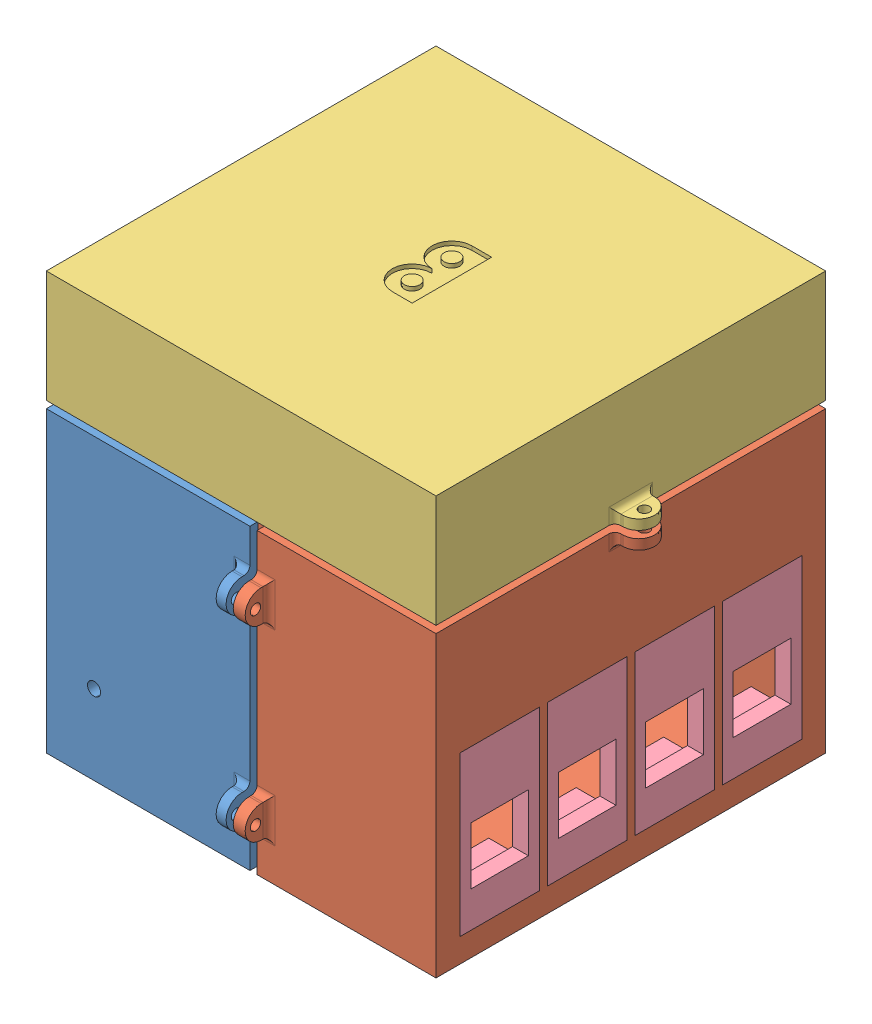
SolidWorks assembly box2, configuration Default. Lengths in mm.
Overall size (110 105 110).
7 component instances, 4 part files, 6 mates.
Components (placement in the parent):
- 2lx-2: 2lx [Default] at (21.703 36.8071 99.9525) size (57.2 80 110)
- 2rx-4: 2rx [Default] at (68.203 36.8071 99.9525) x (-1 0 0) z (0 0 -1) size (56 80 110)
- 2top-2: 2top [Default] at (44.203 141.8071 99.9525) x (-1 0 0) z (0 0 1) size (110 28.2 98)
- rj45-2: rj45 [Default] at (93.203 62.8071 132.9525) x (0 1 0) z (0 0 1) size (40 10.9 20)
- rj45-3: rj45 [Default] at (93.203 62.8071 110.9525) x (0 1 0) z (0 0 1) size (40 10.9 20)
- rj45-4: rj45 [Default] at (93.203 62.8071 88.9525) x (0 1 0) z (0 0 1) size (40 10.9 20)
- rj45-6: rj45 [Default] at (93.203 62.8071 66.9525) x (0 1 0) z (0 0 1) size (40 10.9 20)
Mates (geometry in assembly coordinates):
- Coincident1: coincident: point of 2lx-2; point of 2rx-4
- Coincident2: coincident: point of 2lx-2; point of 2top-2
- Coincident3: coincident: point of 2rx-4; point of rj45-2
- Coincident4: coincident: point of 2rx-4; point of rj45-3
- Coincident5: coincident: point of 2rx-4; point of rj45-4
- Coincident6: coincident: point of 2rx-4; point of rj45-6
